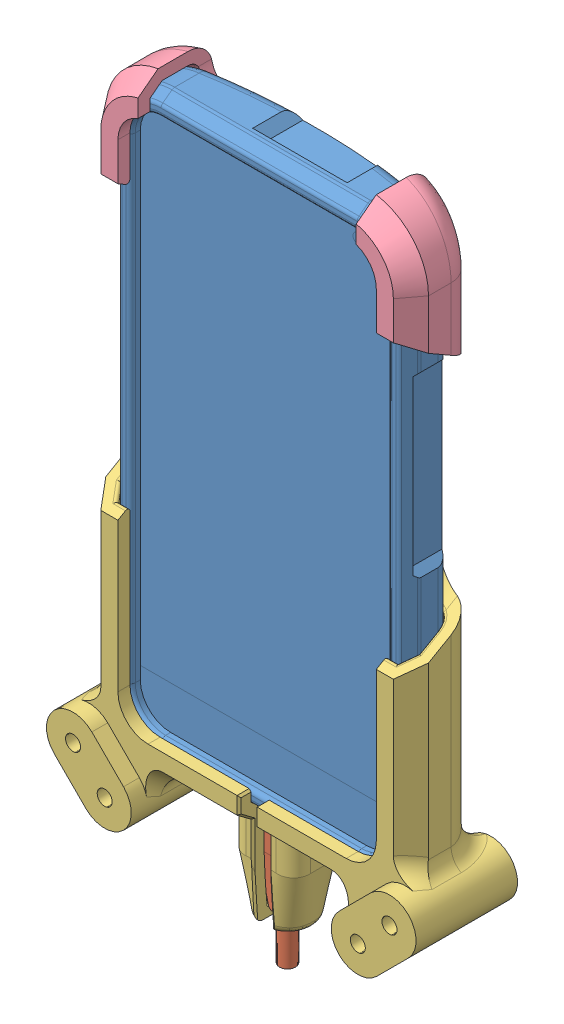
SolidWorks assembly 8699-16-223 Phone Assm, configuration Default. Lengths in mm.
Overall size (93.46 184.83 32.96).
4 component instances, 4 part files, 3 mates.
Components (placement in the parent):
- Phone 2016-1: Phone 2016 [Default] at origin size (74.98 146.37 14.86)
- Phone Cord-1: Phone Cord [Default] at (0 2.286 -7.1755) size (10.16 37.62 7.24)
- 8699-16-329 Phone Holder Btm-1: 8699-16-329 Phone Holder Btm [Default] at origin size (93.46 98.06 32.96)
- 8699-16-330 Phone Holder Top-1: 8699-16-330 Phone Holder Top [Default] at origin size (81.58 105.05 28.96)
Mates (geometry in assembly coordinates):
- Coincident1: coincident aligned: plane of Phone Cord-1 through (0 2.286 -7.1755) normal (1 0 0); plane of assembly through (0 0 0) normal (1 0 0)
- Coincident2: coincident anti-aligned: plane of Phone 2016-1 through (0 2.286 0) normal (0 -1 0); plane of Phone Cord-1 through (0 2.286 -7.1755) normal (0 1 0)
- Distance1: distance = 3.556 mm aligned: plane of Phone Cord-1 through (-5.08 -10.414 -3.556) normal (0 0 1); plane of Phone 2016-1 through (24.7904 12.7 0) normal (0 0 1)
